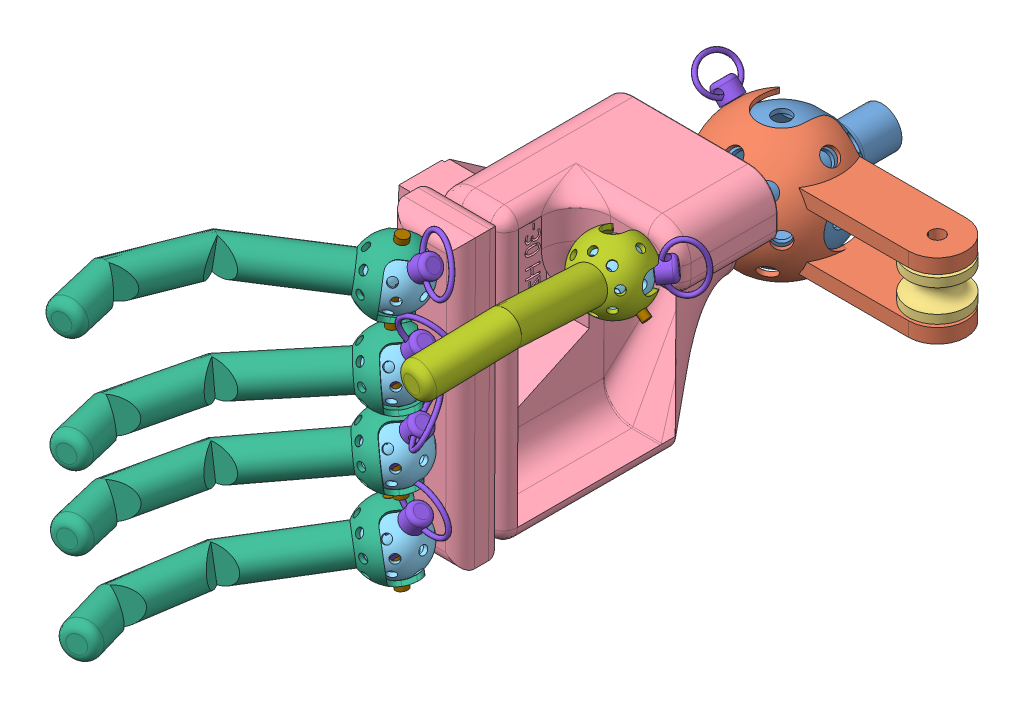
SolidWorks assembly рука, configuration По умолчанию. Lengths in mm.
Overall size (139.18 149.76 257.71).
25 component instances, 9 part files, 0 mates.
Components (placement in the parent):
- Wrist (Ball)-1: Wrist (Ball) [По умолчанию] at (130.9432 19.5819 -34.9204) x (1 0 0) z (0 1 0) size (42 55.8 41.57)
- Wrist (Socket)-1: Wrist (Socket) [По умолчанию] at (130.9432 19.5819 -34.9204) x (1 0 0) z (0 -1 0) size (89.1 37 45.25)
- Wrist (Pulley)-1: Wrist (Pulley) [По умолчанию] at (186.0432 19.5819 -33.9204) x (-0.070211 0 -0.997532) z (0 1 0) size (20 20 14)
- Finger (Hand)-2-1: Finger (Hand)-2 [По умолчанию] at (156.7967 12.6253 74.3496) x (0.004145 0.999991 0) z (0 0 1) size (100.4 77.16 97.92)
- Finger (Ball)-1: Finger (Ball) [По умолчанию] at (131.109 59.5815 99.3496) x (0.811963 0.583709 0) z (-0.583709 0.811963 0) size (20 22.54 19.77)
- Finger (Socket)-1: Finger (Socket) [По умолчанию] at (131.0283 59.0881 99.3496) x (-0.580287 -0.621598 -0.526197) z (-0.352032 0.774074 -0.526197) size (38.39 91.08 37.87)
- Finger (Ball)-2: Finger (Ball) [По умолчанию] at (130.995 32.0818 99.3496) x (-0.772654 0.634827 0) z (-0.634827 -0.772654 0) size (20 22.54 19.77)
- Finger (Socket)-2: Finger (Socket) [По умолчанию] at (131.0437 31.5842 99.3496) x (-0.4251 -0.752117 -0.503598) z (-0.562927 0.655364 -0.503598) size (38.39 91.08 37.87)
- Finger (Ball)-3: Finger (Ball) [По умолчанию] at (130.8913 7.082 99.3496) x (-0.135652 0.990757 0) z (-0.990757 -0.135652 0) size (20 22.54 19.77)
- Finger (Socket)-3: Finger (Socket) [По умолчанию] at (130.8235 7.5774 99.3496) x (-0.398953 -0.768327 -0.500509) z (-0.590794 0.632814 -0.500509) size (38.39 91.08 37.87)
- Finger (Ball)-4: Finger (Ball) [По умолчанию] at (130.7773 -20.4178 99.3496) x (-0.176458 0.984308 0) z (-0.984308 -0.176458 0) size (20 22.54 19.77)
- Finger (Socket)-4: Finger (Socket) [По умолчанию] at (130.6891 -19.9256 99.3496) x (-0.399706 -0.790035 -0.464844) z (-0.649255 0.601987 -0.464844) size (38.39 91.08 37.87)
- Finger (Ball)-5: Finger (Ball) [По умолчанию] at (168.6086 59.4261 60.889) x (-0.15201 0.988379 0) z (-0.988379 -0.15201 0) size (20 22.54 19.77)
- Thumb (Socket)-1: Thumb (Socket) [По умолчанию] at (168.2055 59.7218 60.889) x (-0.161961 0.97481 -0.153344) z (0.978427 0.13844 -0.153344) size (24.44 80.4 23.92)
- Wrist (Lock Pin)-1: Wrist (Lock Pin) [По умолчанию] at (130.8237 59.9784 99.9185) x (0.544202 -0.757007 0.361641) z (0.811963 0.583709 0) size (19.35 7.53 29.68)
- Wrist (Lock Pin)-2: Wrist (Lock Pin) [По умолчанию] at (131.0293 32.0535 100.0983) x (0.711911 -0.584919 -0.388656) z (0.634827 0.772654 0) size (19.35 7.53 29.68)
- Wrist (Lock Pin)-3: Wrist (Lock Pin) [По умолчанию] at (130.3129 7.5211 99.5369) x (0.444577 -0.337498 0.829727) z (0.60465 0.796491 0) size (19.35 7.53 29.68)
- Wrist (Lock Pin)-4: Wrist (Lock Pin) [По умолчанию] at (130.6144 -20.3044 100.0729) x (0.818663 -0.56976 -0.071862) z (0.571237 0.820785 0) size (19.35 7.53 29.68)
- Wrist (Lock Pin)-5: Wrist (Lock Pin) [По умолчанию] at (168.115 59.2086 60.368) x (-0.044313 0.993251 0.107186) z (0.69889 0.107487 -0.707107) size (19.35 7.53 29.68)
- Finger (Pivot Pin, Short)-1: Finger (Pivot Pin, Short) [По умолчанию] at (131.0283 59.0881 99.3496) x (-0.982653 0.160707 0.092552) z (0.1614 0.986889 0) size (4 4 26)
- Finger (Pivot Pin, Short)-2: Finger (Pivot Pin, Short) [По умолчанию] at (131.0437 31.5842 99.3496) x (-0.501883 -0.049147 0.863538) z (-0.097459 0.99524 0) size (4 4 26)
- Finger (Pivot Pin, Short)-3: Finger (Pivot Pin, Short) [По умолчанию] at (130.8235 7.5774 99.3496) x (0.969812 0.132784 0.204533) z (0.135652 -0.990757 0) size (4 4 26)
- Finger (Pivot Pin, Short)-4: Finger (Pivot Pin, Short) [По умолчанию] at (130.6891 -19.9256 99.3496) x (0.982199 0.176079 -0.06543) z (0.176458 -0.984308 0) size (4 4 26)
- Finger (Pivot Pin, Short)-5: Finger (Pivot Pin, Short) [По умолчанию] at (170.2214 58.2433 60.889) x (-0.342638 -0.467186 -0.815069) z (-0.806376 0.591403 0) size (4 4 26)
- Wrist (Lock Pin)-6: Wrist (Lock Pin) [По умолчанию] at (121.5719 30.0096 -34.8536) x (-0.17537 -0.17537 -0.968757) z (-0.707107 0.707107 0) size (19.35 7.53 29.68)
